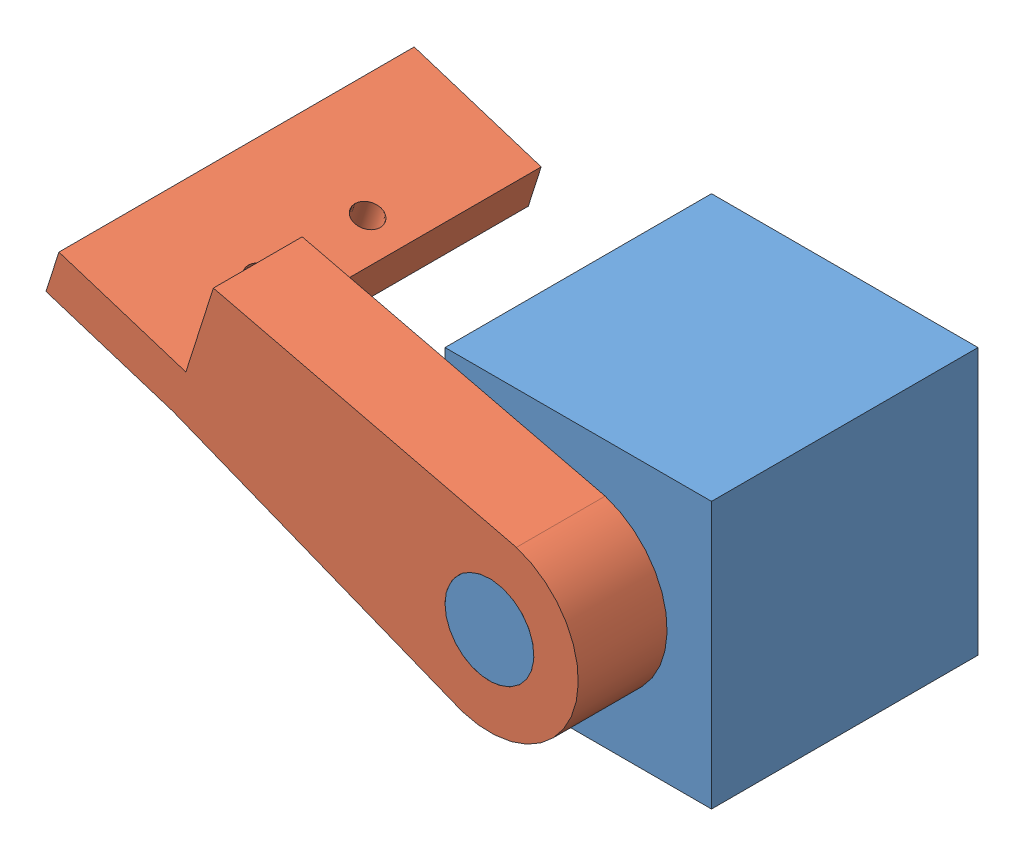
SolidWorks assembly arm, configuration Default. Lengths in mm.
Overall size (65.68 39.68 40).
2 component instances, 2 part files, 1 mates.
Components (placement in the parent):
- Partee3-1: Partee3 [Default] at origin size (30 30 40)
- arm-1: arm [Default] at (0 15 15) x (0.952965 -0.303081 0) z (0 0 1) size (60 20 40)
Mates (geometry in assembly coordinates):
- Hinge1: hinge anti-aligned: cylinder of Partee3-1 through (0 15 25) axis (0 0 -1) radius 5; cylinder of Partee3-1 through (0 15 25) axis (0 0 -1) radius 5; plane of arm-1 through (-15 30 15) normal (0 0 1); plane of arm-1 through (0 15 15) normal (0 0 -1)
